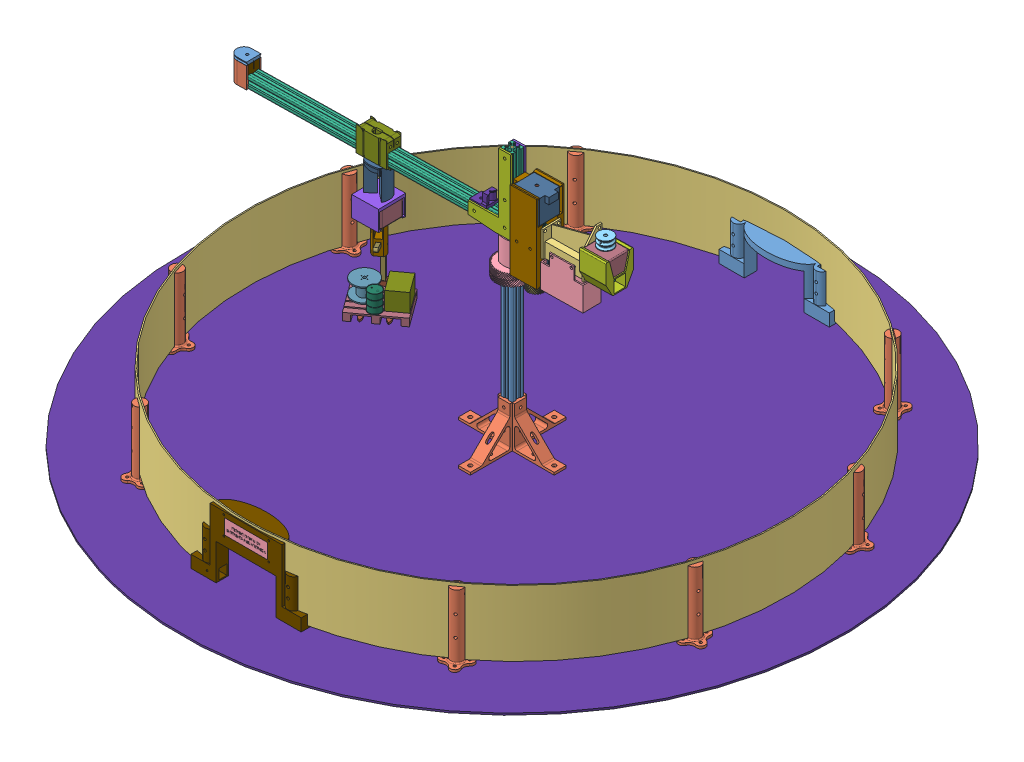
SolidWorks assembly Ensamblaje, configuration Default. Lengths in mm.
Overall size (1330.29 432 1330.29).
54 component instances, 40 part files, 167 mates.
Components (placement in the parent):
- Pieza_1-1: Pieza_1 [Predeterminado] at (126.0044 3.9426 224.652) size (20 300 20)
- Pieza_2-1: Pieza_2 [Predeterminado] at (126.0044 3.9426 224.652) x (-1 0 0) z (0 1 0) size (71.3 20 70)
- Pieza_2-2: Pieza_2 [Predeterminado] at (126.0044 3.9426 224.652) x (0 0 -1) z (0 1 0) size (71.3 20 70)
- Pieza_2-3: Pieza_2 [Predeterminado] at (126.0044 3.9426 224.652) x (1 0 0) z (0 1 0) size (71.3 20 70)
- Pieza_2-4: Pieza_2 [Predeterminado] at (126.0044 3.9426 224.652) x (0 0 1) z (0 1 0) size (71.3 20 70)
- Pieza_3-1: Pieza_3 [Predeterminado] at (126.0044 3.9426 224.652) x (0.334684 0 -0.94233) z (0.94233 0 0.334684) size (4.2 429 4.2)
- Pieza_4-2: Pieza_4 [Predeterminado] at (126.0044 3.9426 224.652) x (0 0 -1) z (0 1 0) size (54.37 54.37 58.71)
- Pieza_5-2: Pieza_5 [Predeterminado] at (126.0044 303.9426 224.652) x (-0.519675 0 0.854364) z (-0.854364 0 -0.519675) size (24 9 24)
- Pieza_6-1: Pieza_6 [Predeterminado] at (285.9827 322.9426 222.0157) x (0 1 0) z (0.016477 0 0.999864) size (20 600 20)
- Pieza_7-2: Pieza_7 [Predeterminado] at (126.0044 3.9426 224.652) x (-0.016477 0 -0.999864) z (0 1 0) size (3 78 124)
- Pieza_8-1: Pieza_8 [Predeterminado] at (126.0044 3.9426 224.652) x (0.016477 0 0.999864) z (0 -1 0) size (3 78 124)
- Pieza_9-2: Pieza_9 [Predeterminado] at (126.5061 3.8426 224.7437) x (-0.016477 0 -0.999864) z (0 1 0) size (46 51 130.1)
- Pieza_10_1-1: Pieza_10_1 [Predeterminado] at (187.8439 397.5426 244.7358) x (-0.999864 0 0.016477) z (0 -1 0) size (48.5 42 41.3)
- Pieza_10_1-3: Pieza_10_1 [Predeterminado] at (186.8424 310.7426 244.6523) x (-0.999864 0 0.016477) z (0 -1 0) size (48.5 42 41.3)
- Pieza_10_2-1: Pieza_10_2 [Default] at (166.5007 350.5426 224.0847) x (0.307585 0 0.951521) z (0.951521 0 -0.307585) size (5 61 5)
- Pieza_10_2-2: Pieza_10_2 [Default] at (165.4992 263.2426 224.0012) x (-0.994213 0 0.107424) z (0.107424 0 0.994213) size (5 61 5)
- Pieza_11-2: Pieza_11 [Predeterminado] at (126.5269 3.9426 222.5392) x (0.037425 0 -0.999299) z (0 1 0) size (28.75 28.65 19.01)
- Pieza_12_1-1: Pieza_12_1 [Predeterminado] at (258.8359 334.8426 243.6659) x (0.999864 0 -0.016477) z (0 1 0) size (42 42 30.3)
- Pieza_12_1-2: Pieza_12_1 [Predeterminado] at (-113.0589 252.5426 249.2444) x (-0.016477 0 -0.999864) z (0 -1 0) size (42 42 30.3)
- Pieza_12_2-1: Pieza_12_2 [Default] at (279.487 335.8426 222.3228) x (0.994746 0 -0.102378) z (0.102378 0 0.994746) size (5 45 5)
- Pieza_12_2-2: Pieza_12_2 [Default] at (-92.4077 206.5426 227.9012) size (5 45 5)
- Pieza_13-2: Pieza_13 [Predeterminado] at (178.8041 6.5426 262.1455) x (-0.951521 0 0.307585) z (0 1 0) size (24 24 12)
- Pieza_14_2-1: Pieza_14_2 [Predeterminado] at (221.5513 3.6926 222.8274) x (-0.016477 0 -0.999864) z (0 1 0) size (24.5 50 45.2)
- Pieza_15-1: Pieza_15 [Predeterminado] at (104.0144 3.9426 225.4387) x (-0.016477 0 -0.999864) z (0 1 0) size (20 28 20)
- Pieza_16-2: Pieza_16 [Predeterminado] at (126.004 3.9426 224.652) x (-0.016477 0 -0.999864) z (0 1 0) size (20 25.56 16.05)
- Pieza_17-2: Pieza_17 [Predeterminado] at (126.004 3.9426 224.652) x (-0.016477 0 -0.999864) z (0 1 0) size (24.5 27.81 5)
- Pieza_18-3: Pieza_18 [Predeterminado] at (126.004 3.9426 224.652) x (-0.016477 0 -0.999864) z (0 1 0) size (24.5 27.81 35)
- Pieza_19-1: Pieza_19 [Predeterminado] at (223.4938 322.7926 223.1955) x (0.016477 0 0.999864) z (-0.999864 0 0.016477) size (31 69.65 70)
- Pieza_20-1: Pieza_20 [Predeterminado] at (223.516 266.7926 224.5453) x (-0.016477 0 -0.999864) z (0.999864 0 -0.016477) size (31 60.15 70)
- Pieza_21-1: Pieza_21 [Predeterminado] at (256.8685 4.8426 85.1756) x (0.986672 0 -0.162724) z (0 1 0) size (24 24 15)
- Pieza_22-1: Pieza_22 [Predeterminado] at (126.0044 332.9426 224.652) x (-0.016477 0 -0.999864) z (0.999864 0 -0.016477) size (20 100 20)
- Pieza_23-1: Pieza_23 [Predeterminado] at (418.4663 3.8426 219.9325) x (0.016477 0 0.999864) z (0 1 0) size (46 44 53)
- Pieza_24-1: Pieza_24 [Predeterminado] at (221.5513 22.7926 222.8274) x (-0.016477 0 -0.999864) z (0 1 0) size (46.2 44 33.9)
- Pieza_25-1: Pieza_25 [Predeterminado] at (-280.0849 55.6036 -28.0723) x (-0.80646 0 0.591288) z (0 1 0) size (20.5 16.25 47)
- Pieza_26-2: Pieza_26 [Predeterminado] at (221.5513 92.9866 222.8274) x (-0.016477 0 -0.999864) z (0 1 0) size (29.46 34.69 49)
- Pieza_27-1: Pieza_27 [Predeterminado] at (-279.3143 56.1235 -26.6831) x (-0.80646 0 0.591288) z (0 1 0) size (42 79 13)
- Pieza_28-1: Pieza_28 [Predeterminado] at (-278.895 56.1235 -26.6185) x (-0.80646 0 0.591288) z (0 1 0) size (6 65.26 99.92)
- Pieza_29-2: Pieza_29 [Predeterminado] at (-81.422 92.73 213.0356) x (0.80646 0 -0.591288) z (0.591288 0 0.80646) size (80 12.5 60)
- Pieza_30-1: Pieza_30 [Predeterminado] at (-111.5826 105.23 233.3743) size (40 25 40)
- Pieza_31-2: Pieza_31 [Predeterminado] at (-81.4243 105.23 246.6022) size (21 30 21)
- Pieza_32-1: Pieza_32 [Predeterminado] at (-70.8844 135.23 215.3147) x (-0.591288 0 -0.80646) z (-0.80646 0 0.591288) size (40 30 30)
- Pieza_33-1: Pieza_33 [Default] at (126.0044 0.9426 224.652) x (0.971237 0 0.238116) z (-0.238116 0 0.971237) size (1100 3 1100)
- Pieza_34-1: Pieza_34 [Default] at (129.5783 33.9426 672.3014) size (184 110 40.87)
- Pieza_35-1: Pieza_35 [Default] at (129.5783 33.9426 -229.772) x (-1 0 0) z (0 0 -1) size (184 70 52.59)
- Pieza_36-1: Pieza_36 [Default] at (559.1125 3.9426 353.444) x (0.294116 0 -0.95577) z (0.95577 0 0.294116) size (46 110 46)
- Pieza_36-2: Pieza_36 [Default] at (393.736 3.9426 584.8465) x (0.809017 0 -0.587785) z (0.587785 0 0.809017) size (46 110 46)
- Pieza_36-3: Pieza_36 [Default] at (-134.5793 3.9426 584.8465) x (0.809017 0 0.587785) z (-0.587785 0 0.809017) size (46 110 46)
- Pieza_36-4: Pieza_36 [Default] at (-297.8377 3.9426 360.1406) x (0.309017 0 0.951057) z (-0.951057 0 0.309017) size (46 110 46)
- Pieza_36-5: Pieza_36 [Default] at (-295.6152 3.9426 75.7262) x (0.323842 0 -0.946111) z (0.946111 0 0.323842) size (46 110 46)
- Pieza_36-6: Pieza_36 [Default] at (-134.5793 3.9426 -142.3171) x (0.809017 0 -0.587785) z (0.587785 0 0.809017) size (46 110 46)
- Pieza_36-7: Pieza_36 [Default] at (556.9944 3.9426 82.3888) x (0.309017 0 0.951057) z (-0.951057 0 0.309017) size (46 110 46)
- Pieza_36-8: Pieza_36 [Default] at (393.736 3.9426 -142.3171) x (0.809017 0 0.587785) z (-0.587785 0 0.809017) size (46 110 46)
- Pieza_37-2: Pieza_37 [Default] at (129.5783 7.9426 221.2647) size (900 110 900)
- Pieza_38-1: Pieza_38 [Default] at (129.5783 92.6926 662.3014) size (71.5 25 10.25)
Mates (geometry in assembly coordinates):
- Coincidente2: coincident aligned: plane of Pieza_1-1 through (134.7044 3.9426 221.312) normal (0 -1 0); plane of Pieza_2-1 through (137.3544 3.9426 224.652) normal (0 -1 0)
- Coincidente3: coincident anti-aligned: plane of Pieza_1-1 through (136.0044 303.9426 232.652) normal (1 0 0); plane of Pieza_2-1 through (136.0044 3.9426 228.792) normal (-1 0 0)
- Coincidente4: coincident aligned: plane of Pieza_1-1 through (134.0044 303.9426 234.652) normal (0 0 1); plane of Pieza_2-1 through (136.0044 3.9426 234.652) normal (0 0 1)
- Coincidente5: coincident aligned: plane of Pieza_1-1 through (134.7044 3.9426 221.312) normal (0 -1 0); plane of Pieza_2-2 through (126.0044 3.9426 236.002) normal (0 -1 0)
- Coincidente6: coincident anti-aligned: plane of Pieza_1-1 through (118.0044 303.9426 234.652) normal (0 0 1); plane of Pieza_2-2 through (121.8644 3.9426 234.652) normal (0 0 -1)
- Coincidente7: coincident aligned: plane of Pieza_1-1 through (116.0044 303.9426 232.652) normal (-1 0 0); plane of Pieza_2-2 through (116.0044 3.9426 234.652) normal (-1 0 0)
- Coincidente8: coincident aligned: plane of Pieza_1-1 through (134.7044 3.9426 221.312) normal (0 -1 0); plane of Pieza_2-3 through (114.6544 3.9426 224.652) normal (0 -1 0)
- Coincidente10: coincident aligned: plane of Pieza_1-1 through (118.0044 303.9426 214.652) normal (0 0 -1); plane of Pieza_2-3 through (116.0044 3.9426 214.652) normal (0 0 -1)
- Coincidente11: coincident anti-aligned: plane of Pieza_1-1 through (116.0044 303.9426 216.652) normal (-1 0 0); plane of Pieza_2-3 through (116.0044 3.9426 220.512) normal (1 0 0)
- Coincidente12: coincident aligned: plane of Pieza_1-1 through (134.7044 3.9426 221.312) normal (0 -1 0); plane of Pieza_2-4 through (126.0044 3.9426 213.302) normal (0 -1 0)
- Coincidente13: coincident anti-aligned: plane of Pieza_1-1 through (134.0044 303.9426 214.652) normal (0 0 -1); plane of Pieza_2-4 through (130.1444 3.9426 214.652) normal (0 0 1)
- Coincidente14: coincident aligned: plane of Pieza_1-1 through (116.0044 303.9426 216.652) normal (-1 0 0); plane of Pieza_2-4 through (116.0044 3.9426 210.652) normal (-1 0 0)
- Concéntrica1: concentric aligned: cylinder of Pieza_1-1 through (126.0044 303.9426 224.652) axis (0 -1 0) radius 2.1; cylinder of Pieza_3-1 through (126.0044 432.9426 224.652) axis (0 -1 0) radius 2.1
- Coincidente15: coincident aligned: plane of Pieza_1-1 through (134.7044 3.9426 221.312) normal (0 -1 0); plane of Pieza_3-1 through (126.0044 3.9426 224.652) normal (0 -1 0)
- Concéntrica5: concentric aligned: cylinder of Pieza_3-1 through (126.0044 432.9426 224.652) axis (0 -1 0) radius 2.1; cylinder of Pieza_4-2 through (126.0044 307.9426 224.652) axis (0 -1 0) radius 12
- Paralelo2: parallel anti-aligned: plane of Pieza_1-1 through (116.0044 303.9426 216.652) normal (-1 0 0); plane of Pieza_4-2 through (115.9544 268.2426 234.702) normal (1 0 0)
- Coincidente20: coincident anti-aligned: plane of Pieza_1-1 through (134.7044 303.9426 221.312) normal (0 1 0); plane of Pieza_4-2 through (126.0044 303.9426 224.652) normal (0 -1 0)
- Concéntrica7: concentric aligned: cylinder of Pieza_3-1 through (126.0044 432.9426 224.652) axis (0 -1 0) radius 2.1; cylinder of Pieza_5-2 through (126.0044 312.9426 224.652) axis (0 -1 0) radius 4
- Coincidente22: coincident anti-aligned: plane of Pieza_1-1 through (134.7044 303.9426 221.312) normal (0 1 0); plane of Pieza_5-2 through (126.0044 303.9426 224.652) normal (0 -1 0)
- Paralelo4: parallel aligned: plane of Pieza_5-2 through (126.0044 312.9426 224.652) normal (0 1 0); plane of Pieza_7-2 through (116.1705 332.9426 234.8154) normal (0 1 0)
- Coincidente27: coincident anti-aligned: plane of Pieza_5-2 through (126.0044 312.9426 224.652) normal (0 1 0); plane of Pieza_7-2 through (126.0044 312.9426 224.652) normal (0 -1 0)
- Concéntrica10: concentric aligned: cylinder of Pieza_5-2 through (126.0044 312.9426 224.652) axis (0 -1 0) radius 12; cylinder of Pieza_7-2 through (126.0044 312.9426 224.652) axis (0 -1 0) radius 12.1
- Coincidente28: coincident anti-aligned: plane of Pieza_5-2 through (126.0044 312.9426 224.652) normal (0 1 0); plane of Pieza_8-1 through (126.0044 312.9426 224.652) normal (0 -1 0)
- Concéntrica11: concentric aligned: cylinder of Pieza_5-2 through (126.0044 312.9426 224.652) axis (0 -1 0) radius 12; cylinder of Pieza_8-1 through (126.0044 312.9426 224.652) axis (0 -1 0) radius 12.1
- Coincidente29: coincident aligned: plane of Pieza_7-2 through (136.1678 332.9426 234.4859) normal (0.999864 0 -0.016477); plane of Pieza_8-1 through (135.8383 332.9426 214.4886) normal (0.999864 0 -0.016477)
- Concéntrica12: concentric anti-aligned: cylinder of Pieza_3-1 through (126.0044 432.9426 224.652) axis (0 -1 0) radius 2.1; cylinder of Pieza_6-1 through (126.0044 147.9426 224.652) axis (0 1 0) radius 2.1
- Coincidente30: coincident anti-aligned: plane of Pieza_7-2 through (105.172 370.9426 234.9967) normal (-0.016477 0 -0.999864); plane of Pieza_6-1 through (-313.7711 314.9426 241.9005) normal (0.016477 0 0.999864)
- Coincidente31: coincident aligned: plane of Pieza_8-1 through (126.0044 312.9426 224.652) normal (0 -1 0); plane of Pieza_6-1 through (-314.0677 312.9426 223.9029) normal (0 -1 0)
- Coincidente43: coincident anti-aligned: plane of Pieza_6-1 through (-314.0677 332.9426 223.9029) normal (0 1 0); plane of Pieza_14_2-1 through (-93.2371 332.9426 238.2663) normal (0 -1 0)
- Coincidente44: coincident anti-aligned: plane of Pieza_6-1 through (-313.7711 314.9426 241.9005) normal (0.016477 0 0.999864); plane of Pieza_14_2-1 through (-93.2371 312.4426 238.2663) normal (-0.016477 0 -0.999864)
- Coincidente48: coincident aligned: plane of Pieza_7-2 through (66.1773 332.9426 235.6393) normal (-0.999864 0 0.016477); plane of Pieza_15-1 through (65.8548 332.9426 216.0662) normal (-0.999864 0 0.016477)
- Coincidente49: coincident anti-aligned: plane of Pieza_6-1 through (-313.8891 331.6426 234.7415) normal (-0.011651 0.707107 -0.707011); plane of Pieza_15-1 through (66.0807 332.9426 229.7801) normal (0.011651 -0.707107 0.707011)
- Tangente3: tangent anti-aligned: cylinder of Pieza_6-1 through (-313.8041 330.9426 239.9008) axis (0.999864 0 -0.016477) radius 2; plane of Pieza_15-1 through (80.0176 332.9426 225.8341) normal (0 -1 0)
- Concéntrica15: concentric aligned: cylinder of Pieza_3-1 through (126.0044 432.9426 224.652) axis (0 -1 0) radius 2.1; cylinder of Pieza_22-1 through (126.0044 432.9426 224.652) axis (0 -1 0) radius 2.1
- Coincidente60: coincident anti-aligned: plane of Pieza_6-1 through (-313.8041 332.9426 239.9008) normal (0 1 0); plane of Pieza_22-1 through (122.5215 332.9426 216.0082) normal (0 -1 0)
- Paralelo11: parallel aligned: plane of Pieza_6-1 through (285.9276 331.6426 218.6761) normal (0.999864 0 -0.016477); plane of Pieza_22-1 through (135.8712 432.9426 216.4883) normal (0.999864 0 -0.016477)
- Coincidente62: coincident aligned: plane of Pieza_8-1 through (135.8383 432.9426 214.4886) normal (0 1 0); plane of Pieza_22-1 through (122.5215 432.9426 216.0082) normal (0 1 0)
- Coincidente65: coincident anti-aligned: plane of Pieza_6-1 through (-314.1007 330.9426 221.9032) normal (-0.016477 0 -0.999864); plane of Pieza_19-1 through (188.3313 312.6426 213.6235) normal (0.016477 0 0.999864)
- Coincidente66: coincident anti-aligned: plane of Pieza_6-1 through (-313.8041 332.9426 239.9008) normal (0 1 0); plane of Pieza_19-1 through (188.3313 332.9426 213.6235) normal (0 -1 0)
- Coincidente72: coincident anti-aligned: plane of Pieza_6-1 through (-314.0677 332.9426 223.9029) normal (0 1 0); plane of Pieza_16-2 through (-311.1545 332.9426 231.856) normal (0 -1 0)
- Coincidente73: coincident aligned: plane of Pieza_6-1 through (-314.1007 330.9426 221.9032) normal (-0.016477 0 -0.999864); plane of Pieza_16-2 through (-298.5388 332.9426 221.6467) normal (-0.016477 0 -0.999864)
- Coincidente74: coincident aligned: plane of Pieza_6-1 through (-313.9909 331.6426 228.5623) normal (-0.999864 0 0.016477); plane of Pieza_16-2 through (-313.9359 332.4176 231.9018) normal (-0.999864 0 0.016477)
- Concéntrica18: concentric anti-aligned: cylinder of Pieza_16-2 through (-309.0369 347.9426 231.8211) axis (0 -1 0) radius 2.1; cylinder of Pieza_17-2 through (-309.0369 347.9426 231.8211) axis (0 1 0) radius 2.1
- Coincidente75: coincident aligned: plane of Pieza_16-2 through (-298.2092 332.9426 241.644) normal (0.999864 0 -0.016477); plane of Pieza_17-2 through (-298.1722 347.9426 243.8937) normal (0.999864 0 -0.016477)
- Coincidente78: coincident anti-aligned: plane of Pieza_16-2 through (-303.0368 347.9426 236.9729) normal (0 1 0); plane of Pieza_17-2 through (-312.2793 347.9426 231.8745) normal (0 -1 0)
- Coincidente80: coincident aligned: plane of Pieza_16-2 through (-298.2092 332.9426 241.644) normal (0.999864 0 -0.016477); plane of Pieza_18-3 through (-298.5758 332.9426 219.3971) normal (0.999864 0 -0.016477)
- Coincidente81: coincident anti-aligned: plane of Pieza_16-2 through (-298.5388 332.9426 221.6467) normal (-0.016477 0 -0.999864); plane of Pieza_18-3 through (-298.5388 332.9426 221.6467) normal (0.016477 0 0.999864)
- Coincidente82: coincident anti-aligned: plane of Pieza_17-2 through (-312.2793 347.9426 231.8745) normal (0 -1 0); plane of Pieza_18-3 through (-312.2793 347.9426 231.8745) normal (0 1 0)
- Concéntrica19: concentric anti-aligned: cylinder of Pieza_19-1 through (239.2362 322.7926 207.434) axis (0.016477 0 0.999864) radius 2.1; cylinder of Pieza_20-1 through (239.7693 322.7926 239.7796) axis (-0.016477 0 -0.999864) radius 2.15
- Coincidente83: coincident anti-aligned: plane of Pieza_19-1 through (188.2984 310.6426 211.6238) normal (-0.016477 0 -0.999864); plane of Pieza_20-1 through (256.2891 306.7926 210.5034) normal (0.016477 0 0.999864)
- Concéntrica21: concentric anti-aligned: cylinder of Pieza_19-1 through (207.2406 322.7926 207.9612) axis (0.016477 0 0.999864) radius 2.1; cylinder of Pieza_20-1 through (207.7736 322.7926 240.3068) axis (-0.016477 0 -0.999864) radius 2.15
- Coincidente84: coincident anti-aligned: plane of Pieza_6-1 through (-314.0677 332.9426 223.9029) normal (0 1 0); plane of Pieza_23-1 through (258.3218 332.9426 212.4702) normal (0 -1 0)
- Coincidente85: coincident anti-aligned: plane of Pieza_6-1 through (-314.1007 330.9426 221.9032) normal (-0.016477 0 -0.999864); plane of Pieza_23-1 through (258.3218 312.7426 212.4702) normal (0.016477 0 0.999864)
- Paralelo12: parallel anti-aligned: plane of Pieza_14_2-1 through (221.5513 306.4426 222.8274) normal (0 -1 0); plane of Pieza_24-1 through (-92.4061 257.4426 228.0012) normal (0 1 0)
- Paralelo13: parallel aligned: plane of Pieza_14_2-1 through (-112.2015 344.6426 240.5791) normal (0.016477 0 0.999864); plane of Pieza_24-1 through (221.9319 22.7926 245.9243) normal (0.016477 0 0.999864)
- Concéntrica23: concentric aligned: cylinder of Pieza_24-1 through (-102.9438 252.5426 228.1748) axis (0 -1 0) radius 2.1; cylinder of Pieza_26-2 through (-102.9438 306.4426 228.1748) axis (0 -1 0) radius 2.1
- Concéntrica24: concentric aligned: cylinder of Pieza_24-1 through (-83.8681 252.5426 227.8605) axis (0 -1 0) radius 2.1; cylinder of Pieza_26-2 through (-83.8681 306.4426 227.8605) axis (0 -1 0) radius 2.1
- Coincidente94: coincident anti-aligned: plane of Pieza_24-1 through (-92.4061 257.4426 228.0012) normal (0 1 0); plane of Pieza_26-2 through (-83.8986 257.4426 227.861) normal (0 -1 0)
- Concéntrica28: concentric aligned: cylinder of Pieza_14_2-1 through (-79.594 310.4426 216.4885) axis (0 1 0) radius 0.55; cylinder of Pieza_26-2 through (-79.594 287.4426 216.4885) axis (0 1 0) radius 0.55
- Concéntrica29: concentric anti-aligned: cylinder of Pieza_14_2-1 through (-107.2179 310.4426 239.5468) axis (0 -1 0) radius 0.55; cylinder of Pieza_26-2 through (-107.2179 287.4426 239.5468) axis (0 1 0) radius 0.55
- Distancia6: distance = 0 mm anti-aligned: plane of Pieza_14_2-1 through (221.5513 306.4426 222.8274) normal (0 -1 0); plane of Pieza_26-2 through (-93.4059 306.4426 228.0177) normal (0 1 0)
- Coincidente105: coincident anti-aligned: plane of Pieza_25-1 through (-99.7114 181.3966 223.1825) normal (-0.186982 0.948683 -0.255025); plane of Pieza_28-1 through (-102.4941 177.0092 208.9016) normal (0.186982 -0.948683 0.255025)
- Coincidente106: coincident anti-aligned: plane of Pieza_25-1 through (-94.7114 181.3966 219.5165) normal (-0.80646 0 0.591288); plane of Pieza_28-1 through (-73.2721 196.6451 248.7575) normal (0.80646 0 -0.591288)
- Distancia3: distance = 20 mm anti-aligned: plane of Pieza_25-1 through (-102.2518 220.2426 225.045) normal (-0.591288 0 -0.80646); plane of Pieza_28-1 through (-106.5371 99.73 203.3873) normal (0.591288 0 0.80646)
- Coincidente110: coincident anti-aligned: plane of Pieza_28-1 through (-106.5371 99.73 203.3873) normal (0.591288 0 0.80646); plane of Pieza_27-1 through (-106.5371 99.73 203.3873) normal (-0.591288 0 -0.80646)
- Coincidente111: coincident aligned: plane of Pieza_28-1 through (-110.0849 99.73 198.5485) normal (0 -1 0); plane of Pieza_27-1 through (-101.2538 99.73 262.3809) normal (0 -1 0)
- Coincidente112: coincident anti-aligned: plane of Pieza_28-1 through (-73.2721 196.6451 248.7575) normal (0.80646 0 -0.591288); plane of Pieza_27-1 through (-106.5371 99.73 203.3873) normal (-0.80646 0 0.591288)
- Distancia5: distance = 180 mm anti-aligned: plane of Pieza_14_2-1 through (-118.4026 329.0676 228.4296) normal (-0.999864 0 0.016477); plane of Pieza_16-2 through (-298.2092 332.9426 241.644) normal (0.999864 0 -0.016477)
- Coincidente119: coincident anti-aligned: plane of Pieza_27-1 through (-97.4941 102.73 197.625) normal (0.591288 0 0.80646); plane of Pieza_29-2 through (-140.2365 102.73 228.9633) normal (-0.591288 0 -0.80646)
- Coincidente120: coincident anti-aligned: plane of Pieza_27-1 through (-101.2538 102.73 262.3809) normal (0 1 0); plane of Pieza_29-2 through (-81.422 102.73 213.0356) normal (0 -1 0)
- Distancia9: distance = 10 mm anti-aligned: plane of Pieza_27-1 through (-95.9879 102.73 187.8408) normal (0.80646 0 -0.591288); plane of Pieza_29-2 through (-83.7843 102.73 187.5731) normal (-0.80646 0 0.591288)
- Paralelo17: parallel aligned: plane of Pieza_29-2 through (-104.7592 102.73 277.3509) normal (0.591288 0 0.80646); plane of Pieza_32-1 through (-46.9617 105.23 222.5745) normal (0.591288 0 0.80646)
- Paralelo18: parallel anti-aligned: plane of Pieza_29-2 through (-40.2424 105.23 230.0478) normal (0.80646 0 -0.591288); plane of Pieza_32-1 through (-71.1555 105.23 240.3132) normal (-0.80646 0 0.591288)
- Distancia16: distance = 31 mm anti-aligned: plane of Pieza_32-1 through (-71.1555 105.23 240.3132) normal (-0.80646 0 0.591288); plane of Pieza_29-2 through (-40.2424 105.23 230.0478) normal (0.80646 0 -0.591288)
- Coincidente129: coincident anti-aligned: plane of Pieza_29-2 through (-81.422 105.23 213.0356) normal (0 1 0); plane of Pieza_32-1 through (-70.8844 105.23 215.3147) normal (0 -1 0)
- Distancia17: distance = 50 mm anti-aligned: plane of Pieza_32-1 through (-70.6132 105.23 190.3161) normal (-0.591288 0 -0.80646); plane of Pieza_29-2 through (-104.7592 102.73 277.3509) normal (0.591288 0 0.80646)
- Coincidente131: coincident anti-aligned: plane of Pieza_29-2 through (-81.422 105.23 213.0356) normal (0 1 0); plane of Pieza_30-1 through (-111.5826 105.23 233.3743) normal (0 -1 0)
- Coincidente134: coincident anti-aligned: plane of Pieza_29-2 through (-81.422 105.23 213.0356) normal (0 1 0); plane of Pieza_31-2 through (-81.4243 105.23 246.6022) normal (0 -1 0)
- Distancia21: distance = 20.5 mm: cylinder of Pieza_30-1 through (-111.5826 105.23 233.3743) axis (0 1 0) radius 2.5; plane of Pieza_29-2 through (-140.2365 102.73 228.9633) normal (-0.80646 0 0.591288)
- Distancia23: distance = 20.5 mm: cylinder of Pieza_30-1 through (-111.5826 105.23 233.3743) axis (0 1 0) radius 2.5; plane of Pieza_29-2 through (-140.2365 102.73 228.9633) normal (-0.591288 0 -0.80646)
- Distancia24: distance = 11 mm: cylinder of Pieza_31-2 through (-81.4243 135.23 246.6022) axis (0 -1 0) radius 10; plane of Pieza_29-2 through (-104.7592 102.73 277.3509) normal (0.591288 0 0.80646)
- Distancia25: distance = 37 mm: cylinder of Pieza_31-2 through (-81.4243 135.23 246.6022) axis (0 -1 0) radius 10; plane of Pieza_29-2 through (-140.2365 102.73 228.9633) normal (-0.80646 0 0.591288)
- Coincidente135: coincident anti-aligned: plane of Pieza_23-1 through (300.3161 334.8426 211.7781) normal (0 1 0); plane of Pieza_12_1-1 through (258.8359 334.8426 243.6659) normal (0 -1 0)
- Coincidente136: coincident anti-aligned: plane of Pieza_23-1 through (418.814 3.8426 241.0296) normal (-0.016477 0 -0.999864); plane of Pieza_12_1-1 through (258.8359 334.8426 243.6659) normal (0.016477 0 0.999864)
- Coincidente137: coincident anti-aligned: plane of Pieza_23-1 through (300.8285 361.8426 242.8739) normal (-0.999864 0 0.016477); plane of Pieza_12_1-1 through (300.8302 334.8426 242.9739) normal (0.999864 0 -0.016477)
- Concéntrica30: concentric anti-aligned: cylinder of Pieza_12_1-1 through (279.487 334.8426 222.3228) axis (0 1 0) radius 2.5; cylinder of Pieza_12_2-1 through (279.487 380.8426 222.3228) axis (0 -1 0) radius 2.5
- Concéntrica31: concentric aligned: cylinder of Pieza_21-1 through (279.487 373.6426 222.3228) axis (0 -1 0) radius 2.5; cylinder of Pieza_12_2-1 through (279.487 380.8426 222.3228) axis (0 -1 0) radius 2.5
- Distancia27: distance = 1 mm anti-aligned: plane of Pieza_21-1 through (279.487 366.1426 222.3228) normal (0 -1 0); plane of Pieza_12_1-1 through (281.9867 365.1426 222.2816) normal (0 1 0)
- Distancia28: distance = 1 mm aligned: plane of Pieza_12_2-1 through (279.487 335.8426 222.3228) normal (0 -1 0); plane of Pieza_12_1-1 through (258.8359 334.8426 243.6659) normal (0 -1 0)
- Coincidente141: coincident anti-aligned: plane of Pieza_24-1 through (-92.4061 252.5426 228.0012) normal (0 -1 0); plane of Pieza_12_1-2 through (-113.0589 252.5426 249.2444) normal (0 1 0)
- Coincidente142: coincident anti-aligned: plane of Pieza_24-1 through (221.2036 22.7926 201.7303) normal (0.016477 0 0.999864); plane of Pieza_12_1-2 through (-113.7509 252.5426 207.2501) normal (-0.016477 0 -0.999864)
- Coincidente143: coincident anti-aligned: plane of Pieza_24-1 through (-113.6603 238.9926 212.7493) normal (0.999864 0 -0.016477); plane of Pieza_12_1-2 through (-113.0589 252.5426 249.2444) normal (-0.999864 0 0.016477)
- Concéntrica32: concentric aligned: cylinder of Pieza_12_1-2 through (-92.4077 252.5426 227.9012) axis (0 -1 0) radius 2.5; cylinder of Pieza_12_2-2 through (-92.4077 251.5426 227.9012) axis (0 -1 0) radius 2.5
- Distancia29: distance = 1 mm aligned: plane of Pieza_12_2-2 through (-92.4077 251.5426 227.9012) normal (0 1 0); plane of Pieza_12_1-2 through (-113.0589 252.5426 249.2444) normal (0 1 0)
- Concéntrica33: concentric aligned: cylinder of Pieza_25-1 through (-92.4077 212.2426 227.9012) axis (0 -1 0) radius 2.55; cylinder of Pieza_12_2-2 through (-92.4077 251.5426 227.9012) axis (0 -1 0) radius 2.5
- Distancia30: distance = 2 mm anti-aligned: plane of Pieza_12_1-2 through (-92.4489 222.2426 225.4015) normal (0 -1 0); plane of Pieza_25-1 through (-92.4077 220.2426 227.9012) normal (0 1 0)
- Concéntrica34: concentric aligned: cylinder of Pieza_13-2 through (166.5007 338.5426 224.0847) axis (0 1 0) radius 2.55; cylinder of Pieza_10_2-1 through (166.5007 335.5426 224.0847) axis (0 1 0) radius 2.5
- Paralelo19: parallel anti-aligned: plane of Pieza_13-2 through (168.5034 338.5426 225.6338) normal (-0.307585 0 -0.951521); plane of Pieza_10_2-1 through (165.6886 335.5426 226.4491) normal (0.307585 0 0.951521)
- Concéntrica35: concentric anti-aligned: cylinder of Pieza_10_1-1 through (166.5007 397.5426 224.0847) axis (0 -1 0) radius 2.5; cylinder of Pieza_10_2-1 through (166.5007 335.5426 224.0847) axis (0 1 0) radius 2.5
- Distancia31: distance = 1 mm aligned: plane of Pieza_10_1-1 through (187.8439 397.5426 244.7358) normal (0 1 0); plane of Pieza_10_2-1 through (166.5007 396.5426 224.0847) normal (0 1 0)
- Coincidente149: coincident anti-aligned: plane of Pieza_13-2 through (166.5007 350.5426 224.0847) normal (0 1 0); plane of Pieza_10_2-1 through (166.5007 350.5426 224.0847) normal (0 -1 0)
- Concéntrica43: concentric anti-aligned: cylinder of Pieza_10_2-2 through (165.4992 248.2426 224.0012) axis (0 1 0) radius 2.5; cylinder of Pieza_10_1-3 through (165.4992 310.7426 224.0012) axis (0 -1 0) radius 2.5
- Coincidente175: coincident aligned: plane of Pieza_4-2 through (126.0044 268.2426 224.652) normal (0 1 0); plane of Pieza_11-2 through (165.4996 268.2426 223.9987) normal (0 1 0)
- Relación de posición de engranaje2: gear = 26 : 52 mm: circle of Pieza_4-2; point of Pieza_11-2
- Distancia33: distance = 39.5 mm: point of Pieza_4-2; unknown of Pieza_11-2
- Coincidente180: coincident anti-aligned: plane of Pieza_6-1 through (-314.0677 332.9426 223.9029) normal (0 1 0); plane of Pieza_9-2 through (186.3332 332.9426 213.7565) normal (0 -1 0)
- Coincidente181: coincident anti-aligned: plane of Pieza_6-1 through (-314.1007 330.9426 221.9032) normal (-0.016477 0 -0.999864); plane of Pieza_9-2 through (186.3316 312.8426 213.6565) normal (0.016477 0 0.999864)
- Coincidente182: coincident anti-aligned: plane of Pieza_10_1-1 through (187.8439 358.1426 244.7358) normal (0 -1 0); plane of Pieza_9-2 through (166.5007 358.1426 224.0847) normal (0 1 0)
- Coincidente183: coincident anti-aligned: plane of Pieza_10_1-1 through (145.1576 358.1426 203.4335) normal (-0.999864 0 0.016477); plane of Pieza_9-2 through (145.5036 377.8426 224.4307) normal (0.999864 0 -0.016477)
- Coincidente184: coincident anti-aligned: plane of Pieza_10_1-1 through (187.1518 358.1426 202.7415) normal (-0.016477 0 -0.999864); plane of Pieza_9-2 through (187.1518 358.1426 202.7415) normal (0.016477 0 0.999864)
- Coincidente185: coincident anti-aligned: plane of Pieza_10_1-3 through (186.8424 271.3426 244.6523) normal (0 -1 0); plane of Pieza_9-2 through (186.2179 271.3426 206.7574) normal (0 1 0)
- Coincidente186: coincident anti-aligned: plane of Pieza_10_1-3 through (186.8424 271.3426 244.6523) normal (0.999864 0 -0.016477); plane of Pieza_9-2 through (186.498 302.1426 223.7551) normal (-0.999864 0 0.016477)
- Concéntrica48: concentric aligned: cylinder of Pieza_10_2-2 through (165.4992 248.2426 224.0012) axis (0 1 0) radius 2.5; circle of Pieza_11-2
- Paralelo26: parallel anti-aligned: plane of Pieza_10_2-2 through (163.3496 248.2426 222.7247) normal (-0.994213 0 0.107424); plane of Pieza_11-2 through (163.258 263.2426 222.7206) normal (0.994213 0 -0.107424)
- Coincidente188: coincident anti-aligned: plane of Pieza_10_2-2 through (165.4992 263.2426 224.0012) normal (0 -1 0); plane of Pieza_11-2 through (163.2842 263.2426 224.2324) normal (0 1 0)
- Coincidente189: coincident anti-aligned: plane of Pieza_10_1-3 through (186.1503 271.3426 202.658) normal (-0.016477 0 -0.999864); plane of Pieza_9-2 through (186.1503 271.4426 202.658) normal (0.016477 0 0.999864)
- Coincidente190: coincident anti-aligned: plane of Pieza_19-1 through (188.4986 322.7926 223.7722) normal (-0.999864 0 0.016477); plane of Pieza_9-2 through (188.1517 312.8426 202.725) normal (0.999864 0 -0.016477)
- Coincidente191: coincident anti-aligned: plane of Pieza_19-1 through (258.489 322.7926 222.6188) normal (0.999864 0 -0.016477); plane of Pieza_23-1 through (258.8342 361.8426 243.5659) normal (-0.999864 0 0.016477)
- Paralelo27: parallel anti-aligned: plane of Pieza_9-2 through (137.5047 376.8426 224.5625) normal (-0.999864 0 0.016477); plane of Pieza_22-1 through (135.8712 432.9426 216.4883) normal (0.999864 0 -0.016477)
- Concéntrica49: concentric aligned: circle of Pieza_1-1; circle of Pieza_33-1
- Coincidente192: coincident anti-aligned: plane of Pieza_2-1 through (137.3544 3.9426 224.652) normal (0 -1 0); plane of Pieza_33-1 through (126.0044 3.9426 224.652) normal (0 1 0)
- Coincidente201: coincident anti-aligned: plane of Pieza_33-1 through (126.0044 3.9426 224.652) normal (0 1 0); plane of Pieza_36-1 through (559.1125 3.9426 353.444) normal (0 -1 0)
- Coincidente202: coincident: moEndPointRef_w of Pieza_36-1
- Coincidente203: coincident: unknown of Pieza_36-1
- Coincidente215: coincident anti-aligned: plane of Pieza_33-1 through (126.0044 3.9426 224.652) normal (0 1 0); plane of Pieza_36-2 through (393.736 3.9426 584.8465) normal (0 -1 0)
- Coincidente216: coincident: unknown of Pieza_36-2
- Coincidente217: coincident: unknown of Pieza_36-2
- Coincidente219: coincident anti-aligned: plane of Pieza_33-1 through (126.0044 3.9426 224.652) normal (0 1 0); plane of Pieza_36-3 through (-134.5793 3.9426 584.8465) normal (0 -1 0)
- Coincidente220: coincident: unknown of Pieza_36-3
- Coincidente221: coincident: unknown of Pieza_36-3
- Coincidente223: coincident anti-aligned: plane of Pieza_33-1 through (126.0044 3.9426 224.652) normal (0 1 0); plane of Pieza_36-4 through (-297.8377 3.9426 360.1406) normal (0 -1 0)
- Coincidente224: coincident: unknown of Pieza_36-4
- Coincidente225: coincident: unknown of Pieza_36-4
- Coincidente226: coincident anti-aligned: plane of Pieza_33-1 through (126.0044 3.9426 224.652) normal (0 1 0); plane of Pieza_36-5 through (-295.6152 3.9426 75.7262) normal (0 -1 0)
- Coincidente228: coincident: unknown of Pieza_36-5
- Coincidente229: coincident: unknown of Pieza_36-5
- Coincidente231: coincident anti-aligned: plane of Pieza_33-1 through (126.0044 3.9426 224.652) normal (0 1 0); plane of Pieza_36-6 through (-134.5793 3.9426 -142.3171) normal (0 -1 0)
- Coincidente232: coincident: unknown of Pieza_36-6
- Coincidente233: coincident: unknown of Pieza_36-6
- Coincidente234: coincident anti-aligned: plane of Pieza_33-1 through (126.0044 3.9426 224.652) normal (0 1 0); plane of Pieza_36-7 through (556.9944 3.9426 82.3888) normal (0 -1 0)
- Coincidente237: coincident: unknown of Pieza_36-7
- Coincidente238: coincident: unknown of Pieza_36-7
- Coincidente239: coincident anti-aligned: plane of Pieza_33-1 through (126.0044 3.9426 224.652) normal (0 1 0); plane of Pieza_36-8 through (393.736 3.9426 -142.3171) normal (0 -1 0)
- Coincidente240: coincident: unknown of Pieza_36-8
- Coincidente241: coincident: unknown of Pieza_36-8
- Coincidente242: coincident anti-aligned: plane of Pieza_33-1 through (126.0044 3.9426 224.652) normal (0 1 0); plane of Pieza_35-1 through (129.5783 3.9426 -225.272) normal (0 -1 0)
- Coincidente246: coincident anti-aligned: plane of Pieza_33-1 through (126.0044 3.9426 224.652) normal (0 1 0); plane of Pieza_34-1 through (129.5783 3.9426 667.8014) normal (0 -1 0)
- Coincidente259: coincident: unknown of Pieza_34-1
- Coincidente260: coincident: line of Pieza_34-1
- Distancia48: distance = 50 mm: line of Pieza_34-1 through (79.5783 3.9426 672.3014) axis (0 1 0)
- Distancia49: distance = 0 mm: line of Pieza_36-8 through (385.8596 7.9426 -131.4763) axis (0 -1 0)
- Distancia50: distance = 0 mm: line of Pieza_36-7 through (544.2502 7.9426 86.5296) axis (0 -1 0)
- Distancia51: distance = 0 mm: line of Pieza_36-1 through (546.3052 7.9426 349.5029) axis (0 -1 0)
- Distancia52: distance = 0 mm: line of Pieza_36-2 through (385.8596 7.9426 574.0057) axis (0 -1 0)
- Distancia53: distance = 0 mm: line of Pieza_36-3 through (-126.703 7.9426 574.0057) axis (0 -1 0)
- Distancia55: distance = 0 mm: line of Pieza_36-4 through (-285.0936 7.9426 355.9998) axis (0 -1 0)
- Distancia56: distance = 0 mm: line of Pieza_36-5 through (-282.9373 7.9426 80.0657) axis (0 -1 0)
- Distancia57: distance = 0 mm: line of Pieza_36-6 through (-126.703 7.9426 -131.4763) axis (0 -1 0)
- Coincidente272: coincident: unknown of Pieza_35-1
- Coincidente273: coincident: unknown of Pieza_35-1
- Distancia58: distance = 50 mm: line of Pieza_35-1 through (179.5783 3.9426 -208.6889) axis (0 1 0)
- Coincidente302: coincident anti-aligned: plane of Pieza-2 through (129.5783 7.9426 221.2647) normal (0 -1 0); plane of Pieza_36-2 through (393.736 7.9426 584.8465) normal (0 1 0)
- Concéntrica53: concentric aligned: circle of Pieza-2
- Coincidente303: coincident: plane of Pieza_34-1 through (221.5783 33.9426 672.3014) normal (1 0 0); line of Pieza_37-2 through (221.5783 7.9426 661.7599) axis (0 1 0)
- Coincidente304: coincident anti-aligned: plane of Pieza_34-1 through (93.8283 33.9426 667.8014) normal (1 0 0); plane of Pieza_38-1 through (93.8283 105.1926 672.3014) normal (-1 0 0)
- Coincidente305: coincident anti-aligned: plane of Pieza_34-1 through (129.5783 105.1926 667.8014) normal (0 -1 0); plane of Pieza_38-1 through (93.8283 105.1926 672.3014) normal (0 1 0)
- Coincidente306: coincident aligned: plane of Pieza_34-1 through (129.5783 33.9426 672.3014) normal (0 0 1); plane of Pieza_38-1 through (129.5783 92.6926 672.3014) normal (0 0 1)
